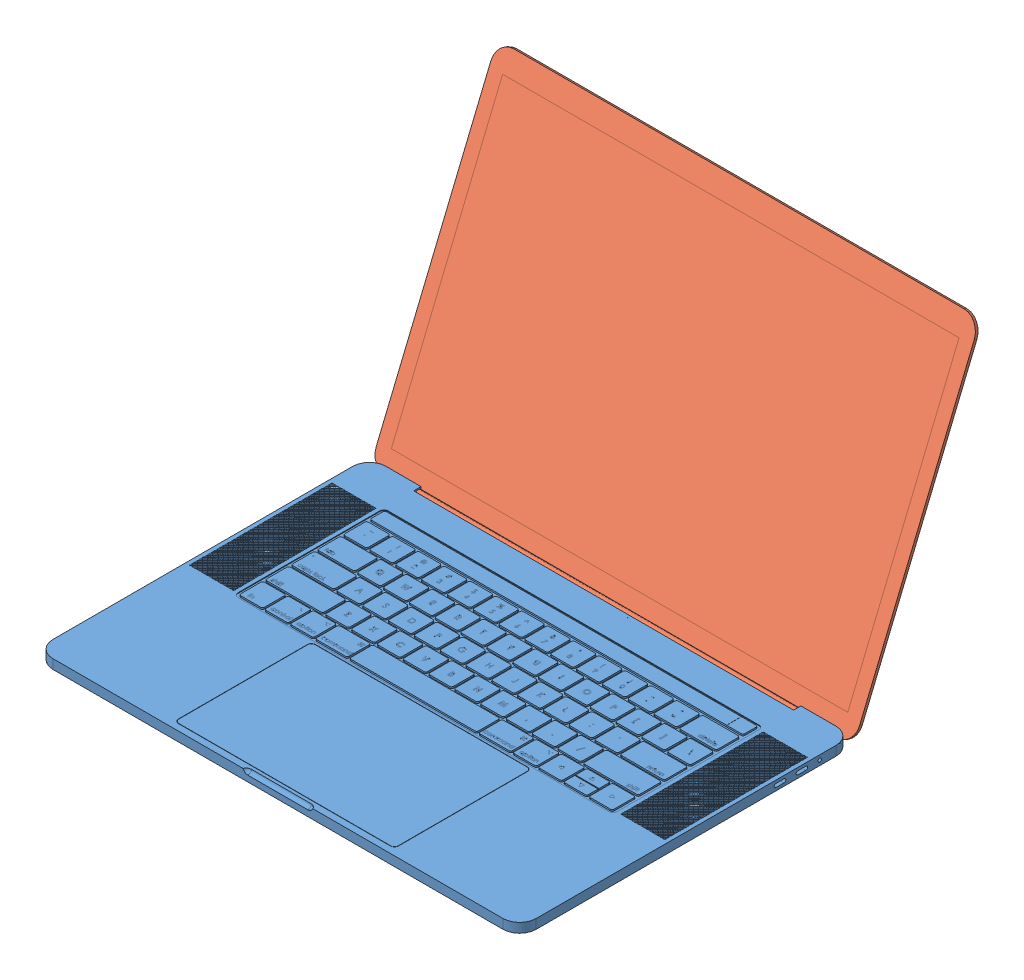
SolidWorks assembly laptop, configuration Default. Lengths in mm.
Overall size (349.4 227.7 338.22).
2 component instances, 2 part files, 3 mates.
Components (placement in the parent):
- better base plate-1: better base plate [Default] at (146.7955 136.2425 291.8245) size (349.3 10.5 240.7)
- screen-1: screen [Default] at (146.8955 242.7896 123.2467) x (-1 0 0) z (0 0.92388 -0.382683) size (349.3 12.3 240.7)
Mates (geometry in assembly coordinates):
- Concentric1: concentric: circle of better base plate-1; circle of screen-1
- Coincident14: coincident: plane of better base plate-1 through (284.0455 129.6425 171.4745) normal (-1 0 0); plane of screen-1 through (284.0455 135.9425 173.7745) normal (1 0 0)
- LimitAngle1: limit planar angle = 1.963495 rad: plane of screen-1 through (-27.7545 132.4017 171.2363) normal (0 0.382683 0.92388); plane of better base plate-1 through (321.4455 139.6425 171.4745) normal (0 1 0)
